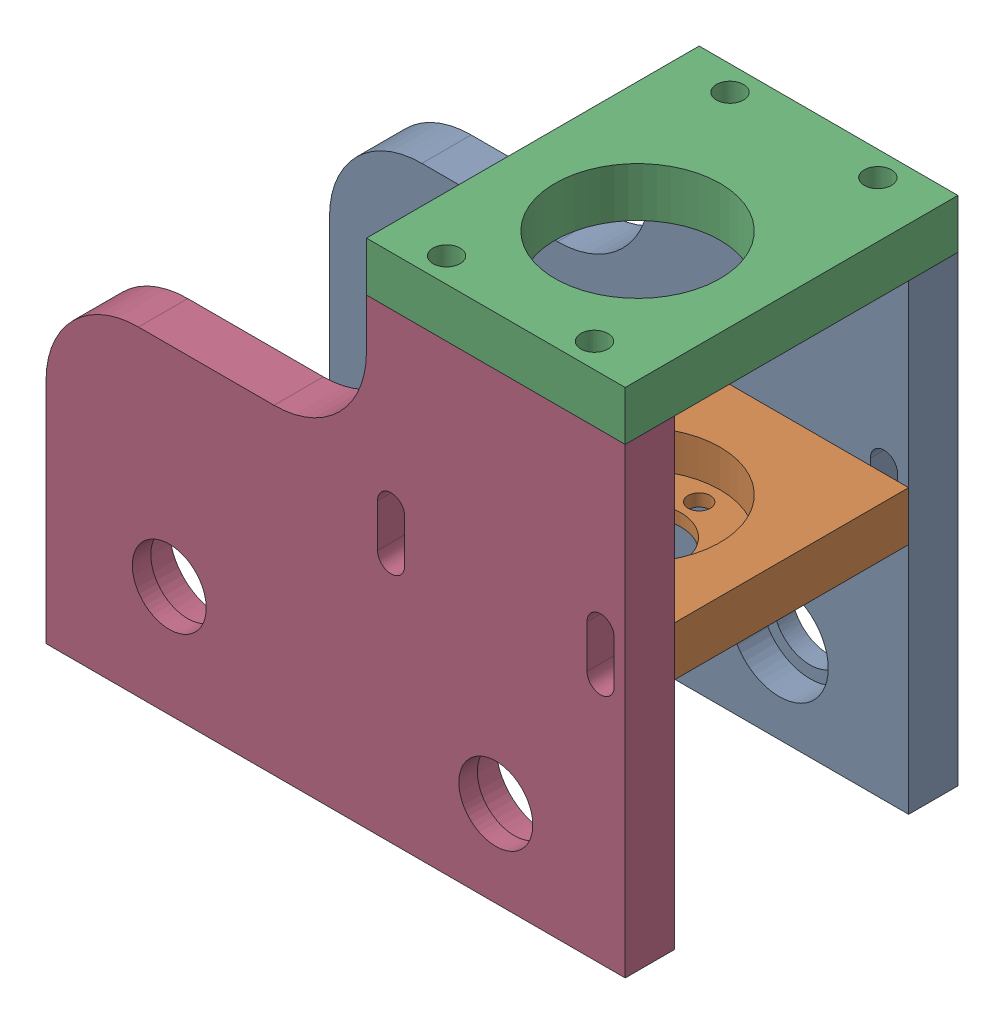
SolidWorks assembly Assemblage_Bloc_Moteur_Gauche_Allege, configuration Défaut. Lengths in mm.
Overall size (94 83 54).
4 component instances, 4 part files, 8 mates.
Components (placement in the parent):
- Plaque_Droite_Bloc_Moteur_Gauche-1: Plaque_Droite_Bloc_Moteur_Gauche [Défaut] at (-58.4997 -25.1585 106.4462) size (94 75 8)
- Plaque_Support_Moteur-1: Plaque_Support_Moteur [Défaut] at (35.5003 12.7614 114.4462) x (-1 0 0) z (0 0 -1) size (42 8 38)
- Plaque_Axe_Moteur-1: Plaque_Axe_Moteur [Défaut] at (35.5003 49.8415 106.4462) x (-1 0 0) z (0 0 -1) size (42 8 54)
- Plaque_Gauche_Bloc_Moteur_Gauche-1: Plaque_Gauche_Bloc_Moteur_Gauche [Défaut] at (-58.4997 -25.1585 152.4462) size (94 75 8)
Mates (geometry in assembly coordinates):
- Coïncidente11: coincident anti-aligned: plane of Plaque_Droite_Bloc_Moteur_Gauche-1 through (-58.4997 49.8415 114.4462) normal (0 1 0); plane of Plaque_Axe_Moteur-1 through (35.5003 49.8415 106.4462) normal (0 -1 0)
- Coïncidente12: coincident aligned: plane of Plaque_Droite_Bloc_Moteur_Gauche-1 through (-58.4997 -25.1585 114.4462) normal (0 -1 0); plane of Plaque_Gauche_Bloc_Moteur_Gauche-1 through (-58.4997 -25.1585 160.4462) normal (0 -1 0)
- Coaxiale18: concentric aligned: cylinder of Plaque_Axe_Moteur-1 through (26.5003 49.8415 156.4462) axis (0 1 0) radius 2.2; cylinder of Plaque_Gauche_Bloc_Moteur_Gauche-1 through (26.5003 19.8415 156.4462) axis (0 1 0) radius 1.5
- Coaxiale19: concentric aligned: cylinder of Plaque_Axe_Moteur-1 through (2.5003 49.8415 156.4462) axis (0 1 0) radius 2.2; cylinder of Plaque_Gauche_Bloc_Moteur_Gauche-1 through (2.5003 19.8415 156.4462) axis (0 1 0) radius 1.5
- Coïncidente21: coincident anti-aligned: plane of Plaque_Droite_Bloc_Moteur_Gauche-1 through (-58.4997 -25.1585 114.4462) normal (0 0 1); plane of Plaque_Support_Moteur-1 through (35.5003 20.7614 114.4462) normal (0 0 -1)
- Coaxiale20: concentric aligned: cylinder of Plaque_Droite_Bloc_Moteur_Gauche-1 through (26.5003 19.8415 110.4462) axis (0 1 0) radius 1.5; cylinder of Plaque_Axe_Moteur-1 through (26.5003 49.8415 110.4462) axis (0 1 0) radius 2.2
- Rainure2: slot anti-aligned: cylinder of Plaque_Gauche_Bloc_Moteur_Gauche-1 through (31.5003 14.8415 160.4462) axis (0 0 -1) radius 2.2; cylinder of Plaque_Support_Moteur-1 through (31.5003 16.7614 114.4462) axis (0 0 1) radius 1.5; cylinder of Plaque_Gauche_Bloc_Moteur_Gauche-1 through (31.5003 21.8415 160.4462) axis (0 0 -1) radius 2.2
- Rainure3: slot anti-aligned: cylinder of Plaque_Gauche_Bloc_Moteur_Gauche-1 through (-2.4997 14.8415 160.4462) axis (0 0 -1) radius 2.2; cylinder of Plaque_Support_Moteur-1 through (-2.4997 16.7614 114.4462) axis (0 0 1) radius 1.5; cylinder of Plaque_Gauche_Bloc_Moteur_Gauche-1 through (-2.4997 21.8415 160.4462) axis (0 0 -1) radius 2.2
